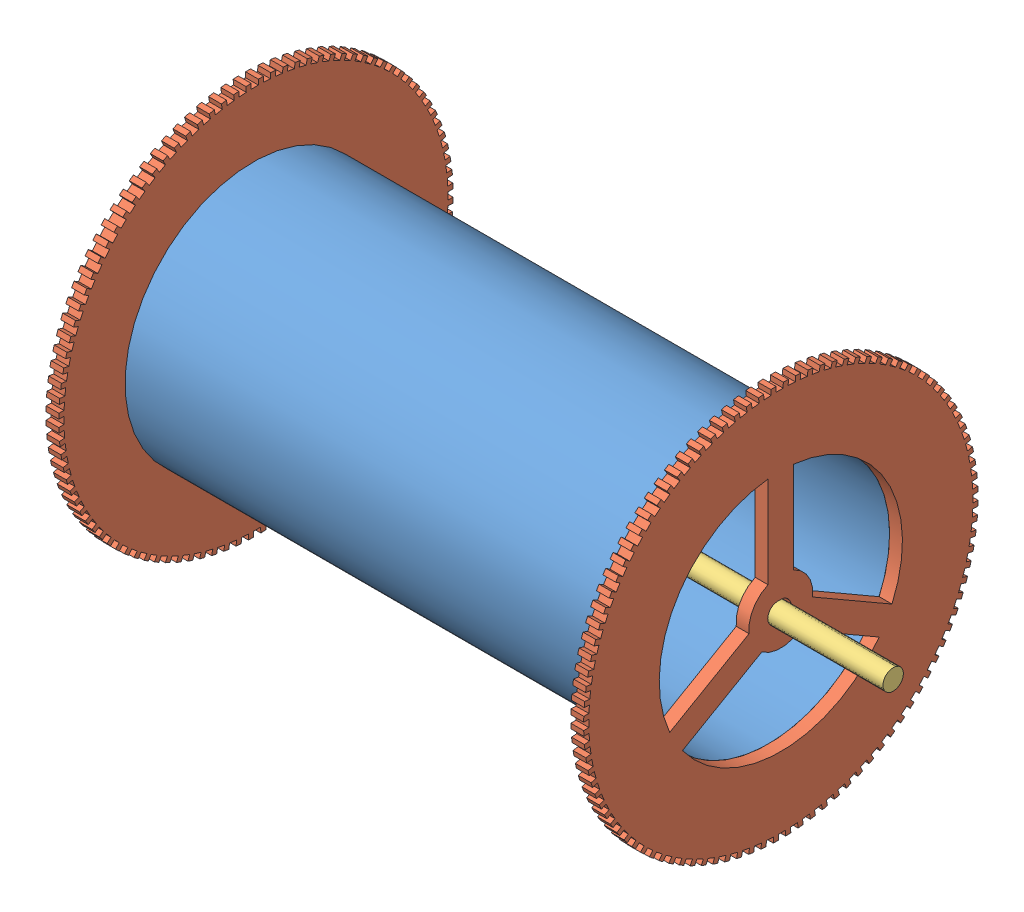
SolidWorks assembly drumroll_assembly_V2, configuration Default. Lengths in mm.
Overall size (300 154.01 154.01).
4 component instances, 3 part files, 5 mates.
Components (placement in the parent):
- drumroll_V2-1: drumroll_V2 [Default] at origin size (200 100 100)
- drumroll_V2_end-2: drumroll_V2_end [Default] at (100 0 -1.1204) size (5 154.01 154.01)
- drumroll_V2_end-3: drumroll_V2_end [Default] at (-105 0 -1.1204) size (5 154.01 154.01)
- drum_smooth_rod-1: drum_smooth_rod [Default] at origin size (300 8 8)
Mates (geometry in assembly coordinates):
- Coincident5: coincident anti-aligned: plane of drumroll_V2-1 through (100 0 0) normal (1 0 0); plane of drumroll_V2_end-2 through (100 0 -1.1204) normal (-1 0 0)
- Coincident6: coincident aligned: circle of drumroll_V2-1; circle of drumroll_V2_end-2
- Coincident7: coincident: circle of drumroll_V2-1; circle of drumroll_V2_end-3
- Coincident8: coincident aligned: line of drumroll_V2-1 through (110 0 0) axis (-1 0 0); line of drum_smooth_rod-1 through (165 0 0) axis (-1 0 0)
- Coincident9: coincident aligned: plane of drumroll_V2-1 through (0 0 0) normal (1 0 0); plane of drum_smooth_rod-1 through (0 0 0) normal (1 0 0)
